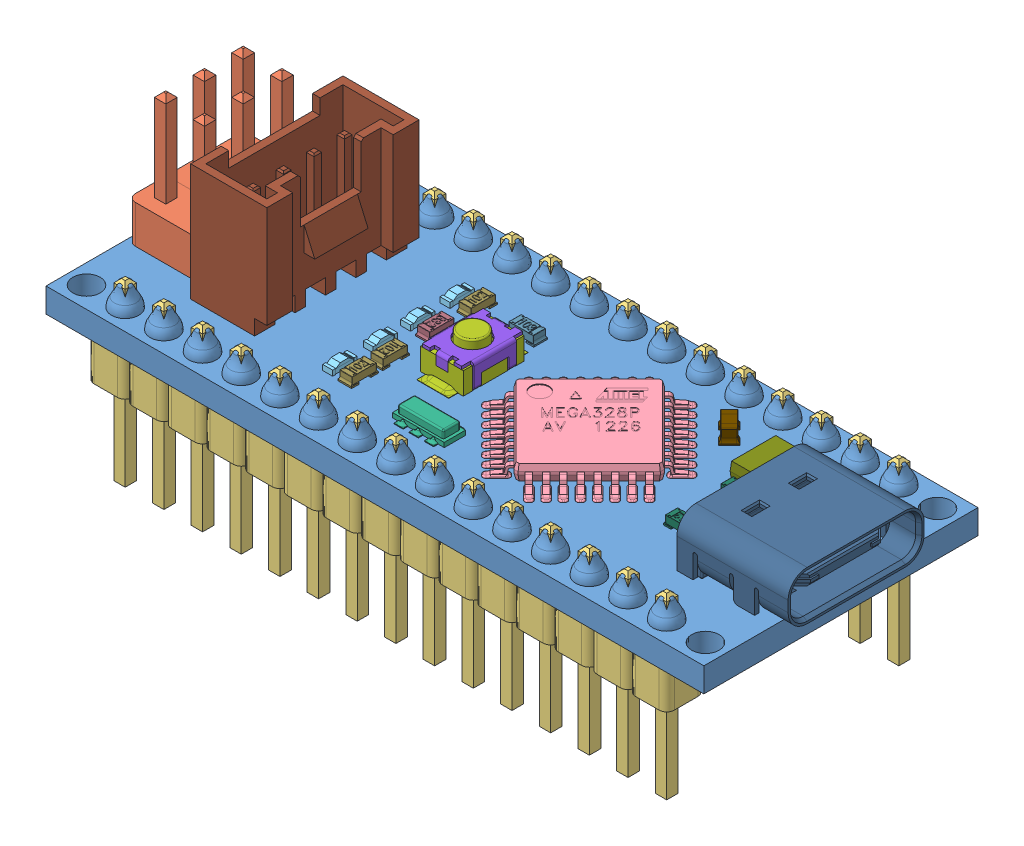
SolidWorks assembly Seeeduino Nano, configuration Default. Lengths in mm.
Overall size (44.2 18.6 18).
44 component instances, 18 part files, 99 mates.
Components (placement in the parent):
- PCB-1: PCB [Default] at origin size (43.2 4.6 18)
- 2pin_header__02-1: 2pin_header__02 [Default] at (-1.143 1.6 -7.62) size (5 11.75 2.54)
- 2pin_header__02-2: 2pin_header__02 [Default] at (-1.143 1.6 -5.08) size (5 11.75 2.54)
- 2pin_header__02-3: 2pin_header__02 [Default] at (-1.143 1.6 -10.16) size (5 11.75 2.54)
- 15pin_header__-1: 15pin_header__ [Default] x (0 0 1) z (1 0 0) size (2.54 11.75 38.1)
- 15pin_header__-2: 15pin_header__ [Default] at (0 0 -15.24) x (0 0 1) z (1 0 0) size (2.54 11.75 38.1)
- ATMega328-1: ATMega328 [Default] at (22.85 1.75 -7.62) x (-0.707107 0 0.707107) z (-0.707107 0 -0.707107) size (10 1.1 10)
- LED-1: LED [Default] at (10.4 1.6 -3.6968) x (0 0 1) z (-1 0 0) size (1.6 0.5 0.65)
- LED-2: LED [Default] at (10.4 1.6 -6.3609) x (0 0 -1) z (1 0 0) size (1.6 0.5 0.65)
- LED-3: LED [Default] at (10.4 1.6 -8.812) x (0 0 1) z (-1 0 0) size (1.6 0.5 0.65)
- LED-4: LED [Default] at (10.4 1.6 -11.3985) x (0 0 -1) z (1 0 0) size (1.6 0.5 0.65)
- 16MHz Crystal-1: 16MHz Crystal [Default] at (16.75 1.6 -3.2) size (3.4 0.8 2)
- Reset Button-1: Reset Button [Default] at (14.75 1.6 -8.05) x (0 0 -1) z (1 0 0) size (5.2 2.15 3)
  - Reset Core-1: Reset Core [Default] at origin size (5.2 2.15 2.8)
  - Reset Shell-1: Reset Shell [Default] at (0 1.65 0) x (0 0 1) z (-1 0 0) size (3 1.65 4)
- Regulator-1: Regulator [Default] at (10.25 0 -6) x (0 0 1) z (1 0 0) size (6.5 1.69 8.3)
- USB-C Female-1: USB-C Female [Default] at (33.08 3.205 -7.62) x (0 0 -1) z (0 -1 0) size (8.94 7.9 5)
- Connector Grove DIP-1: Connector Grove DIP [Défaut] at (6.68 1.6 -7.62) x (0 0 -1) z (1 0 0) size (10 10 5)
- Resistor 102-1: Resistor 102 [Default] at (11.6 1.6 -11.5074) x (0 0 -1) z (1 0 0) size (1.78 0.62 0.92)
- Resistor 102-2: Resistor 102 [Default] at (11.6 1.6 -5.7348) x (0 0 1) z (-1 0 0) size (1.78 0.62 0.92)
- Resistor 102-3: Resistor 102 [Default] at (11.6 1.6 -3.6968) x (0 0 -1) z (1 0 0) size (1.78 0.62 0.92)
- Resistor 332-1: Resistor 332 [Default] at (11.6 1.6 -8.7968) x (0 0 1) z (-1 0 0) size (1.78 0.62 0.92)
- Resistor 103-1: Resistor 103 [Default] at (14.7983 1.6 -11.6) size (1.78 0.62 0.92)
- Resistor 512-1: Resistor 512 [Default] at (30.9223 1.6 -5.75) x (-1 0 0) z (0 0 -1) size (1.78 0.62 0.92)
- Resistor 512-2: Resistor 512 [Default] at (30.9737 1.6 -9.35) x (-1 0 0) z (0 0 -1) size (1.78 0.62 0.92)
- SSOT3-1: SSOT3 [Default] at (30.4209 1.6 -11.5) x (0 0 -1) z (1 0 0) size (3 1.13 3.09)
- Resistor 220-1: Resistor 220 [Default] at (16.5656 0 -7.65) x (1 0 0) z (0 0 -1) size (1.78 0.62 0.92)
- Resistor 102-4: Resistor 102 [Default] at (16.5656 0 -8.8353) x (1 0 0) z (0 0 -1) size (1.78 0.62 0.92)
- Resistor 220-2: Resistor 220 [Default] at (16.5656 0 -10.1199) x (-1 0 0) z (0 0 1) size (1.78 0.62 0.92)
- Resistor 102-5: Resistor 102 [Default] at (16.5656 0 -11.365) x (1 0 0) z (0 0 -1) size (1.78 0.62 0.92)
- Resistor 102-6: Resistor 102 [Default] at (20.8561 0 -4.65) x (1 0 0) z (0 0 -1) size (1.78 0.62 0.92)
- Capacitor 603-1: Capacitor 603 [Default] at (27.0626 1.6 -12.5998) x (0.707107 0 0.707107) z (-0.707107 0 0.707107) size (1.83 0.9 1.08)
- Capacitor 603-2: Capacitor 603 [Default] at (15.38 0 -4.6897) x (0 0 -1) z (-1 0 0) size (1.83 0.9 1.08)
- Capacitor 603-3: Capacitor 603 [Default] at (16.7466 0 -4.6897) x (0 0 -1) z (-1 0 0) size (1.83 0.9 1.08)
- Capacitor 603-4: Capacitor 603 [Default] at (18.6438 0 -2.8782) x (0 0 -1) z (-1 0 0) size (1.83 0.9 1.08)
- Capacitor 603-5: Capacitor 603 [Default] at (18.5292 0 -4.7105) x (-1 0 0) z (0 0 1) size (1.83 0.9 1.08)
- Capacitor 603-6: Capacitor 603 [Default] at (25.4087 0 -3.4271) x (0 0 -1) z (-1 0 0) size (1.83 0.9 1.08)
- Capacitor 603-7: Capacitor 603 [Default] at (26.963 0 -3.4271) x (0 0 -1) z (-1 0 0) size (1.83 0.9 1.08)
- Capacitor 603-8: Capacitor 603 [Default] at (26.7377 0 -6.3937) x (0 0 -1) z (-1 0 0) size (1.83 0.9 1.08)
- Capacitor 603-9: Capacitor 603 [Default] at (30.4421 0 -12.0662) x (-1 0 0) z (0 0 1) size (1.83 0.9 1.08)
- Capacitor 603-10: Capacitor 603 [Default] at (30.4421 0 -13.3256) x (-1 0 0) z (0 0 1) size (1.83 0.9 1.08)
- Capacitor 603-11: Capacitor 603 [Default] at (22.169 0 -11.9928) x (-1 0 0) z (0 0 1) size (1.83 0.9 1.08)
- Capacitor 603-12: Capacitor 603 [Default] at (7.1508 0 -10.6025) x (-1 0 0) z (0 0 1) size (1.83 0.9 1.08)
- Capacitor 603-13: Capacitor 603 [Default] at (7.1508 0 -12.0107) x (-1 0 0) z (0 0 1) size (1.83 0.9 1.08)
Mates (geometry in assembly coordinates):
- Coincident1: coincident anti-aligned: plane of 2pin_header__02-1 through (-3.143 4.1 -8.89) normal (0 0 -1); plane of 2pin_header__02-3 through (0.857 4.1 -8.89) normal (0 0 1)
- Coincident2: coincident anti-aligned: plane of 2pin_header__02-1 through (0.857 4.1 -6.35) normal (0 0 1); plane of 2pin_header__02-2 through (-3.143 4.1 -6.35) normal (0 0 -1)
- Coincident3: coincident aligned: plane of 2pin_header__02-1 through (1.357 4.1 -8.39) normal (1 0 0); plane of 2pin_header__02-2 through (1.357 4.1 -5.85) normal (1 0 0)
- Coincident4: coincident aligned: plane of 2pin_header__02-1 through (1.357 4.1 -8.39) normal (1 0 0); plane of 2pin_header__02-3 through (1.357 4.1 -10.93) normal (1 0 0)
- Coincident5: coincident aligned: plane of 2pin_header__02-1 through (0.857 1.6 -6.85) normal (0 -1 0); plane of 2pin_header__02-3 through (0.857 1.6 -9.39) normal (0 -1 0)
- Coincident6: coincident aligned: plane of 2pin_header__02-1 through (0.857 1.6 -6.85) normal (0 -1 0); plane of 2pin_header__02-2 through (0.857 1.6 -4.31) normal (0 -1 0)
- Coincident7: coincident anti-aligned: plane of nano-board-1 through (0 1.6 0) normal (0 1 0); plane of 2pin_header__02-2 through (0.857 1.6 -4.31) normal (0 -1 0)
- Distance1: distance = 7.62 mm aligned: plane of 2pin_header__02-1 through (-1.143 1.6 -7.62) normal (0 0 1); plane of assembly through (0 0 0) normal (0 0 1)
- Distance2: distance = 1.143 mm aligned: plane of 2pin_header__02-3 through (-1.143 1.6 -10.16) normal (1 0 0); plane of assembly through (0 0 0) normal (1 0 0)
- Coincident10: coincident anti-aligned: plane of nano-board-1 through (0 0 0) normal (0 -1 0); plane of 15pin_header__-1 through (0.77 0 0.77) normal (0 1 0)
- Coincident11: coincident anti-aligned: plane of nano-board-1 through (0 0 0) normal (0 -1 0); plane of 15pin_header__-2 through (0.77 0 -14.47) normal (0 1 0)
- Coincident13: coincident aligned: plane of 15pin_header__-1 through (0 0 0) normal (0 0 1); plane of assembly through (0 0 0) normal (0 0 1)
- Coincident14: coincident aligned: plane of nano-board-1 through (0 0 0) normal (1 0 0); plane of 15pin_header__-1 through (0 0 0) normal (1 0 0)
- Coincident16: coincident aligned: plane of 15pin_header__-2 through (0 0 -15.24) normal (1 0 0); plane of assembly through (0 0 0) normal (1 0 0)
- Distance3: distance = 15.24 mm aligned: plane of 15pin_header__-2 through (0 0 -15.24) normal (0 0 1); plane of assembly through (0 0 0) normal (0 0 1)
- Distance4: distance = 0.15 mm anti-aligned: plane of atmega328-1 through (22.85 1.75 -7.62) normal (0 -1 0); plane of nano-board-1 through (0 1.6 0) normal (0 1 0)
- Distance5: distance = 7.62 mm: line of atmega328-1 through (22.85 1.5954 -7.62) axis (0 1 0); plane of assembly through (0 0 0) normal (0 0 1)
- Angle1: planar angle = 2.356194 rad anti-aligned: plane of atmega328-1 through (22.85 1.75 -7.62) normal (-0.707107 0 0.707107); plane of assembly through (0 0 0) normal (0 0 1)
- Distance6: distance = 22.85 mm: line of atmega328-1 through (22.85 1.5954 -7.62) axis (0 1 0); plane of assembly through (0 0 0) normal (1 0 0)
- Coincident41: coincident aligned: plane of nano-board-1 through (0 1.6 0) normal (0 1 0); plane of led-1 through (10.4 1.6 -3.6968) normal (0 1 0)
- Coincident43: coincident aligned: plane of nano-board-1 through (0 1.6 0) normal (0 1 0); plane of led-2 through (10.4 1.6 -6.3609) normal (0 1 0)
- Coincident44: coincident aligned: plane of nano-board-1 through (0 1.6 0) normal (0 1 0); plane of led-3 through (10.4284 1.6 -8.812) normal (0 1 0)
- Coincident42: coincident aligned: plane of nano-board-1 through (0 1.6 0) normal (0 1 0); plane of led-4 through (10.4284 1.6 -11.3985) normal (0 1 0)
- Coincident53: coincident aligned: plane of nano-board-1 through (0 1.6 0) normal (0 1 0); plane of 16mhz crystal - measured-1 through (16.75 1.6 -3.2) normal (0 1 0)
- Coincident61: coincident aligned: plane of nano-board-1 through (0 1.6 0) normal (0 1 0); plane of reset button-1 through (14.75 1.6 -8.05) normal (0 1 0)
- Distance33: distance = 8.05 mm anti-aligned: plane of reset button-1 through (14.75 1.6 -8.05) normal (0 0 -1); plane of assembly through (0 0 0) normal (0 0 1)
- Distance34: distance = 14.75 mm aligned: plane of reset button-1 through (14.75 1.6 -8.05) normal (1 0 0); plane of assembly through (0 0 0) normal (1 0 0)
- Coïncidente66: coincident anti-aligned: plane of nano-board-1 through (0 0 0) normal (0 -1 0); plane of Regulator-1 through (10.25 0 -6) normal (0 1 0)
- Distance35: distance = 6 mm aligned: plane of nano - reg-1 through (10.25 0 -6) normal (0 0 1); plane of assembly through (0 0 0) normal (0 0 1)
- Distance36: distance = 10.25 mm aligned: plane of nano - reg-1 through (10.25 0 -6) normal (1 0 0); plane of assembly through (0 0 0) normal (1 0 0)
- Coïncidente1: coincident anti-aligned: plane of nano-board-1 through (0 1.6 0) normal (0 1 0); plane of USB-C Female-1 through (40.38 1.6 -3.15) normal (0 -1 0)
- Distance42: distance = 1 mm aligned: plane of nano-board-1 through (39.38 1.6 -16.62) normal (1 0 0); plane of USB-C Female-1 through (40.38 3.205 -7.62) normal (1 0 0)
- Coïncidente3: coincident: point of nano-board-1; plane of USB-C Female-1 through (33.08 3.205 -7.62) normal (0 0 -1)
- Distance44: distance = 16.75 mm aligned: plane of nano-board-1 through (0 0 0) normal (1 0 0); plane of 16mhz crystal - measured-1 through (16.75 1.6 -3.2) normal (1 0 0)
- Distance45: distance = 3.2 mm aligned: plane of nano-board-1 through (0 0 0) normal (0 0 1); plane of 16mhz crystal - measured-1 through (16.75 1.6 -3.2) normal (0 0 1)
- Coïncidente4: coincident anti-aligned: plane of nano-board-1 through (0 1.6 0) normal (0 1 0); plane of Connector Grove DIP-1 through (6.68 1.6 -7.62) normal (0 -1 0)
- Coïncidente6: coincident: unknown of nano-board-1; plane of Connector Grove DIP-1 through (6.68 1.6 -7.62) normal (0 0 -1)
- Distance47: distance = 12 mm aligned: plane of nano-board-1 through (0 0 0) normal (1 0 0); plane of Resistor 102-1 through (12 2.175 -12.2824) normal (1 0 0)
- Coïncidente8: coincident anti-aligned: plane of nano-board-1 through (0 1.6 0) normal (0 1 0); plane of Resistor 102-1 through (11.6 1.6 -11.5074) normal (0 -1 0)
- Coïncidente9: coincident aligned: plane of Resistor 102-1 through (11.2 2.175 -12.2824) normal (-1 0 0); plane of Resistor 102-2 through (11.2 2.175 -4.9598) normal (-1 0 0)
- Coïncidente10: coincident aligned: plane of Resistor 102-1 through (12 2.175 -12.2824) normal (1 0 0); plane of Resistor 102-3 through (12 2.175 -4.4718) normal (1 0 0)
- Coïncidente11: coincident anti-aligned: plane of nano-board-1 through (0 1.6 0) normal (0 1 0); plane of Resistor 102-3 through (11.6 1.6 -3.6968) normal (0 -1 0)
- Coïncidente12: coincident anti-aligned: plane of nano-board-1 through (0 1.6 0) normal (0 1 0); plane of Resistor 102-2 through (11.6 1.6 -5.7348) normal (0 -1 0)
- Coïncidente13: coincident aligned: plane of Resistor 102-2 through (11.2 2.175 -4.9598) normal (-1 0 0); plane of Resistor 332-1 through (11.2 2.175 -8.0218) normal (-1 0 0)
- Coïncidente14: coincident anti-aligned: plane of nano-board-1 through (0 1.6 0) normal (0 1 0); plane of Resistor 332-1 through (11.6 1.6 -8.7968) normal (0 -1 0)
- Coïncidente15: coincident anti-aligned: plane of nano-board-1 through (0 1.6 0) normal (0 1 0); plane of Resistor 103-1 through (14.7983 1.6 -11.6) normal (0 -1 0)
- Distance48: distance = 12 mm anti-aligned: plane of Resistor 103-1 through (15.5733 2.175 -12) normal (0 0 -1); plane of nano-board-1 through (0 0 0) normal (0 0 1)
- Coïncidente18: coincident anti-aligned: plane of nano-board-1 through (0 1.6 0) normal (0 1 0); plane of Resistor 512-1 through (30.9223 1.6 -5.75) normal (0 -1 0)
- Distance49: distance = 5.35 mm aligned: plane of Resistor 512-1 through (30.1473 2.175 -5.35) normal (0 0 1); plane of nano-board-1 through (0 0 0) normal (0 0 1)
- Coïncidente21: coincident anti-aligned: plane of nano-board-1 through (0 1.6 0) normal (0 1 0); plane of Resistor 512-2 through (30.9737 1.6 -9.35) normal (0 -1 0)
- Distance50: distance = 2.8 mm anti-aligned: plane of Resistor 512-1 through (30.1473 2.175 -6.15) normal (0 0 -1); plane of Resistor 512-2 through (30.1987 2.175 -8.95) normal (0 0 1)
- Coïncidente23: coincident anti-aligned: plane of nano-board-1 through (0 1.6 0) normal (0 1 0); plane of SSOT3-1 through (30.4209 1.6 -11.5) normal (0 -1 0)
- Distance52: distance = 11.5 mm anti-aligned: plane of SSOT3-1 through (30.4209 1.6 -11.5) normal (0 0 -1); plane of nano-board-1 through (0 0 0) normal (0 0 1)
- Coïncidente27: coincident anti-aligned: plane of nano-board-1 through (0 0 0) normal (0 -1 0); plane of Resistor 220-1 through (16.5656 0 -7.65) normal (0 1 0)
- Distance53: distance = 7.25 mm aligned: plane of nano-board-1 through (0 0 0) normal (0 0 1); plane of Resistor 220-1 through (17.3406 -0.575 -7.25) normal (0 0 1)
- Coïncidente28: coincident anti-aligned: plane of nano-board-1 through (0 0 0) normal (0 -1 0); plane of Resistor 102-4 through (16.5656 0 -8.8353) normal (0 1 0)
- Coïncidente30: coincident aligned: plane of Resistor 220-1 through (16.5656 0 -7.65) normal (1 0 0); plane of Resistor 102-4 through (16.5656 0 -8.8353) normal (1 0 0)
- Coïncidente31: coincident anti-aligned: plane of nano-board-1 through (0 0 0) normal (0 -1 0); plane of Resistor 220-2 through (16.5656 0 -10.1199) normal (0 1 0)
- Coïncidente33: coincident anti-aligned: plane of Resistor 102-4 through (16.5656 0 -8.8353) normal (1 0 0); plane of Resistor 220-2 through (16.5656 0 -10.1199) normal (-1 0 0)
- Coïncidente34: coincident anti-aligned: plane of nano-board-1 through (0 0 0) normal (0 -1 0); plane of Resistor 102-5 through (16.5656 0 -11.365) normal (0 1 0)
- Coïncidente36: coincident anti-aligned: plane of Resistor 220-2 through (16.5656 0 -10.1199) normal (-1 0 0); plane of Resistor 102-5 through (16.5656 0 -11.365) normal (1 0 0)
- Coïncidente37: coincident anti-aligned: plane of nano-board-1 through (0 0 0) normal (0 -1 0); plane of Resistor 102-6 through (20.8561 0 -4.65) normal (0 1 0)
- Distance54: distance = 4.25 mm aligned: plane of Resistor 102-6 through (21.6311 -0.575 -4.25) normal (0 0 1); plane of nano-board-1 through (0 0 0) normal (0 0 1)
- Distance55: distance = 5.5 mm aligned: plane of Connector Grove DIP-1 through (1.68 9.3 -2.62) normal (-1 0 0); plane of nano-board-1 through (-3.82 1.6 -16.62) normal (-1 0 0)
- Coïncidente40: coincident anti-aligned: plane of nano-board-1 through (0 1.6 0) normal (0 1 0); plane of Capacitor 603-1 through (27.0626 1.6 -12.5998) normal (0 -1 0)
- Distance56: distance = 6.5 mm aligned: plane of atmega328-1 through (22.85 1.75 -7.62) normal (-0.707107 0 0.707107); plane of Capacitor 603-1 through (27.0626 1.6 -12.5998) normal (-0.707107 0 0.707107)
- Coïncidente42: coincident anti-aligned: plane of nano-board-1 through (0 0 0) normal (0 -1 0); plane of Capacitor 603-2 through (15.38 0 -4.6897) normal (0 1 0)
- Distance57: distance = 15 mm anti-aligned: plane of Capacitor 603-2 through (15 -0.125 -5.0897) normal (-1 0 0); plane of nano-board-1 through (0 0 0) normal (1 0 0)
- Coïncidente44: coincident anti-aligned: plane of nano-board-1 through (0 0 0) normal (0 -1 0); plane of Capacitor 603-3 through (16.7466 0 -4.6897) normal (0 1 0)
- Parallèle1: parallel anti-aligned: plane of Capacitor 603-2 through (15.76 -0.125 -5.0897) normal (1 0 0); plane of Capacitor 603-3 through (16.3666 -0.125 -5.0897) normal (-1 0 0)
- Coïncidente46: coincident aligned: plane of Capacitor 603-2 through (15.38 0 -4.6897) normal (0 0 -1); plane of Capacitor 603-3 through (16.7466 0 -4.6897) normal (0 0 -1)
- Coïncidente47: coincident anti-aligned: plane of nano-board-1 through (0 0 0) normal (0 -1 0); plane of Capacitor 603-4 through (18.6438 0 -2.8782) normal (0 1 0)
- Parallèle2: parallel anti-aligned: plane of Capacitor 603-2 through (15.76 -0.125 -5.0897) normal (1 0 0); plane of Capacitor 603-4 through (18.2638 -0.125 -3.2782) normal (-1 0 0)
- Coïncidente48: coincident anti-aligned: plane of nano-board-1 through (0 0 0) normal (0 -1 0); plane of Capacitor 603-5 through (18.5292 0 -4.7105) normal (0 1 0)
- Parallèle3: parallel aligned: plane of nano-board-1 through (0 0 0) normal (0 0 1); plane of Capacitor 603-5 through (18.1292 -0.125 -4.3305) normal (0 0 1)
- Coïncidente50: coincident anti-aligned: plane of nano-board-1 through (0 0 0) normal (0 -1 0); plane of Capacitor 603-6 through (25.4087 0 -3.4271) normal (0 1 0)
- Parallèle4: parallel anti-aligned: plane of Capacitor 603-4 through (19.0238 -0.125 -3.2782) normal (1 0 0); plane of Capacitor 603-6 through (25.0287 -0.125 -3.8271) normal (-1 0 0)
- Coïncidente53: coincident anti-aligned: plane of nano-board-1 through (0 0 0) normal (0 -1 0); plane of Capacitor 603-7 through (26.963 0 -3.4271) normal (0 1 0)
- Parallèle5: parallel anti-aligned: plane of Capacitor 603-6 through (25.7887 -0.125 -3.8271) normal (1 0 0); plane of Capacitor 603-7 through (26.583 -0.125 -3.8271) normal (-1 0 0)
- Coïncidente54: coincident aligned: plane of Capacitor 603-6 through (25.4087 0 -3.4271) normal (0 0 -1); plane of Capacitor 603-7 through (26.963 0 -3.4271) normal (0 0 -1)
- Coïncidente55: coincident anti-aligned: plane of nano-board-1 through (0 0 0) normal (0 -1 0); plane of Capacitor 603-8 through (26.7377 0 -6.3937) normal (0 1 0)
- Parallèle6: parallel anti-aligned: plane of Capacitor 603-6 through (25.7887 -0.125 -3.8271) normal (1 0 0); plane of Capacitor 603-8 through (26.3577 -0.125 -6.7937) normal (-1 0 0)
- Coïncidente57: coincident anti-aligned: plane of nano-board-1 through (0 0 0) normal (0 -1 0); plane of Capacitor 603-9 through (30.4421 0 -12.0662) normal (0 1 0)
- Parallèle7: parallel aligned: plane of nano-board-1 through (0 0 0) normal (0 0 1); plane of Capacitor 603-9 through (30.0421 -0.125 -11.6862) normal (0 0 1)
- Coïncidente58: coincident anti-aligned: plane of nano-board-1 through (0 0 0) normal (0 -1 0); plane of Capacitor 603-10 through (30.4421 0 -13.3256) normal (0 1 0)
- Parallèle8: parallel anti-aligned: plane of Capacitor 603-9 through (30.0421 -0.125 -12.4462) normal (0 0 -1); plane of Capacitor 603-10 through (30.0421 -0.125 -12.9456) normal (0 0 1)
- Coïncidente60: coincident aligned: plane of Capacitor 603-9 through (30.4421 0 -12.0662) normal (-1 0 0); plane of Capacitor 603-10 through (30.4421 0 -13.3256) normal (-1 0 0)
- Coïncidente61: coincident anti-aligned: plane of nano-board-1 through (0 0 0) normal (0 -1 0); plane of Capacitor 603-11 through (22.169 0 -11.9928) normal (0 1 0)
- Parallèle9: parallel aligned: plane of nano-board-1 through (0 0 0) normal (0 0 1); plane of Capacitor 603-11 through (21.769 -0.125 -11.6128) normal (0 0 1)
- Coïncidente62: coincident anti-aligned: plane of nano-board-1 through (0 0 0) normal (0 -1 0); plane of Capacitor 603-12 through (7.1508 0 -10.6025) normal (0 1 0)
- Parallèle10: parallel aligned: plane of nano-board-1 through (0 0 0) normal (0 0 1); plane of Capacitor 603-12 through (6.7508 -0.125 -10.2225) normal (0 0 1)
- Coïncidente63: coincident anti-aligned: plane of nano-board-1 through (0 0 0) normal (0 -1 0); plane of Capacitor 603-13 through (7.1508 0 -12.0107) normal (0 1 0)
- Parallèle11: parallel anti-aligned: plane of Capacitor 603-12 through (6.7508 -0.125 -10.9825) normal (0 0 -1); plane of Capacitor 603-13 through (6.7508 -0.125 -11.6307) normal (0 0 1)
- Coïncidente65: coincident aligned: plane of Capacitor 603-12 through (7.1508 0 -10.6025) normal (-1 0 0); plane of Capacitor 603-13 through (7.1508 0 -12.0107) normal (-1 0 0)
- Distance58: distance = 0.5 mm anti-aligned: plane of led-1 through (10.7 1.9 -4.4468) normal (1 0 0); plane of Resistor 102-3 through (11.2 2.175 -4.4718) normal (-1 0 0)
- Coïncidente68: coincident anti-aligned: plane of led-1 through (10.4 1.6 -3.6968) normal (0 0 1); plane of Resistor 102-3 through (11.6 1.6 -3.6968) normal (0 0 -1)
- Coïncidente75: coincident anti-aligned: plane of led-1 through (10.4 1.6 -3.6968) normal (-1 0 0); plane of led-2 through (10.4 1.6 -6.3609) normal (1 0 0)
- Coïncidente76: coincident anti-aligned: plane of led-4 through (10.4284 1.6 -11.3985) normal (1 0 0); plane of led-3 through (10.4284 1.6 -8.812) normal (-1 0 0)
- Coïncidente77: coincident anti-aligned: plane of led-2 through (10.4 1.6 -6.3609) normal (1 0 0); plane of led-3 through (10.4 1.6 -8.812) normal (-1 0 0)
